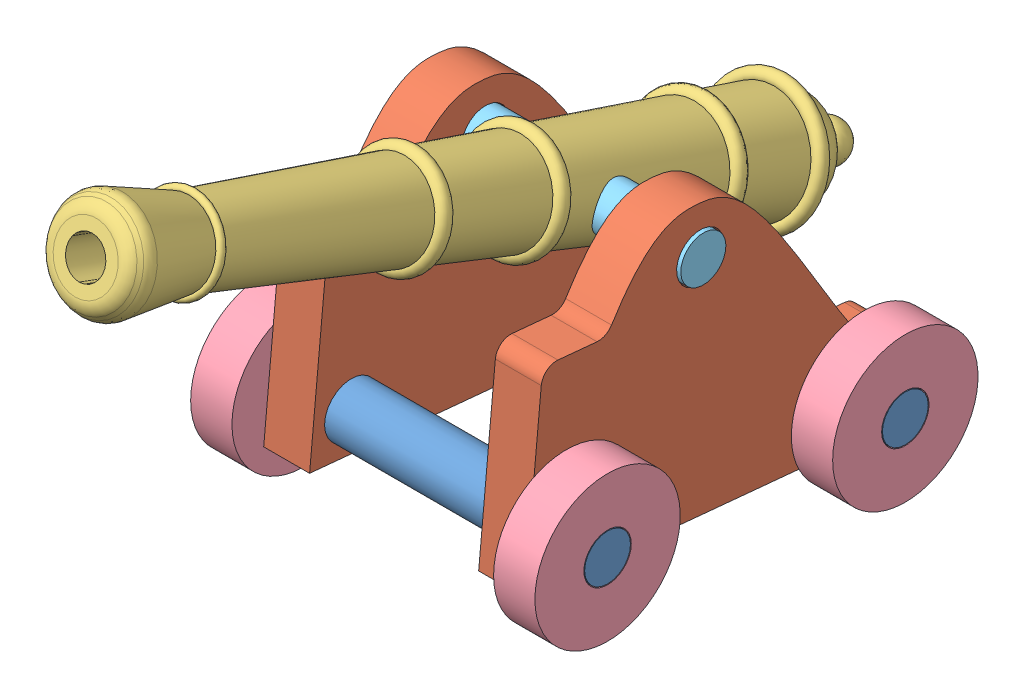
SolidWorks assembly ToyCannon, configuration Default. Lengths in mm.
Overall size (57.15 89.23 132.99).
10 component instances, 5 part files, 21 mates.
Components (placement in the parent):
- Axle-1: Axle [Default] at (20.2048 30.8146 43.7896) size (57.15 8.89 8.89)
- SideSupports-1: SideSupports [Default] at (2.4248 44.3939 17.6176) x (0 0.094911 0.995486) z (-1 0 0) size (62.23 44.95 7.62)
- Axle-2: Axle [Default] at (20.2048 26.1016 -5.6432) size (57.15 8.89 8.89)
- SideSupports-2: SideSupports [Default] at (38.1118 44.3939 17.6176) x (0 0.094911 0.995486) z (-1 0 0) size (62.23 44.95 7.62)
- Barrel-1: Barrel [Default] at (20.2048 65.3462 37.7707) x (1 0 0) z (0 -0.939693 0.34202) size (20.53 134.05 20.53)
- Wheel-1: Wheel [Default] at (-4.8142 26.1016 -5.6432) x (1 0 0) z (0 0.759231 0.650821) size (6.86 24.13 24.13)
- Wheel-2: Wheel [Default] at (-4.9412 30.8146 43.7896) size (6.86 24.13 24.13)
- Wheel-3: Wheel [Default] at (45.3508 26.1016 -5.6432) size (6.86 24.13 24.13)
- Wheel-4: Wheel [Default] at (45.3508 30.8146 43.7896) size (6.86 24.13 24.13)
- BarrelAxle-1: BarrelAxle [Default] at (20.2048 59.4392 21.5414) x (1 0 0) z (0 0.428897 0.903354) size (44.45 7.62 7.62)
Mates (geometry in assembly coordinates):
- Concentric1: concentric anti-aligned: cylinder of Axle-2 through (48.7798 26.1016 -5.6432) axis (-1 0 0) radius 4.445; cylinder of SideSupports-2 through (34.3018 26.1016 -5.6432) axis (1 0 0) radius 3.937
- Concentric2: concentric anti-aligned: cylinder of SideSupports-1 through (-1.3852 26.1016 -5.6432) axis (1 0 0) radius 3.937; cylinder of Axle-2 through (48.7798 26.1016 -5.6432) axis (-1 0 0) radius 4.445
- Concentric3: concentric anti-aligned: cylinder of Axle-1 through (48.7798 30.8146 43.7896) axis (-1 0 0) radius 4.445; cylinder of SideSupports-2 through (34.3018 30.8146 43.7896) axis (1 0 0) radius 3.937
- Concentric4: concentric anti-aligned: cylinder of Axle-1 through (48.7798 30.8146 43.7896) axis (-1 0 0) radius 4.445; cylinder of SideSupports-1 through (-1.3852 30.8146 43.7896) axis (1 0 0) radius 3.937
- Angle1: planar angle = 2.792527 rad aligned: plane of Barrel-1 through (20.2048 65.3462 37.7707) normal (0 -0.939693 0.34202); plane of assembly through (0 0 0) normal (0 1 0)
- Coincident3: coincident aligned: plane of Axle-2 through (20.2048 26.1016 -5.6432) normal (1 0 0); plane of Barrel-1
- Coincident4: coincident aligned: plane of Axle-1 through (20.2048 30.8146 43.7896) normal (1 0 0); plane of Barrel-1
- Concentric8: concentric anti-aligned: cylinder of Axle-1 through (48.7798 30.8146 43.7896) axis (-1 0 0) radius 4.445; cylinder of Wheel-4 through (41.9218 30.8146 43.7896) axis (1 0 0) radius 3.937
- Concentric9: concentric anti-aligned: cylinder of Axle-1 through (48.7798 30.8146 43.7896) axis (-1 0 0) radius 4.445; cylinder of Wheel-2 through (-8.3702 30.8146 43.7896) axis (1 0 0) radius 3.937
- Concentric10: concentric anti-aligned: cylinder of Axle-2 through (48.7798 26.1016 -5.6432) axis (-1 0 0) radius 4.445; cylinder of Wheel-1 through (-8.2432 26.1016 -5.6432) axis (1 0 0) radius 3.937
- Coincident6: coincident aligned: plane of Axle-1 through (-8.3702 30.8146 43.7896) normal (-1 0 0); plane of Wheel-2 through (-8.3702 30.8146 43.7896) normal (-1 0 0)
- Coincident7: coincident aligned: plane of Axle-1 through (48.7798 30.8146 43.7896) normal (1 0 0); plane of Wheel-4 through (48.7798 30.8146 43.7896) normal (1 0 0)
- Coincident8: coincident aligned: plane of Axle-2 through (48.7798 26.1016 -5.6432) normal (1 0 0); plane of Wheel-3 through (48.7798 26.1016 -5.6432) normal (1 0 0)
- Concentric12: concentric anti-aligned: cylinder of Axle-2 through (48.7798 26.1016 -5.6432) axis (-1 0 0) radius 4.445; cylinder of Wheel-3 through (41.9218 26.1016 -5.6432) axis (1 0 0) radius 3.937
- Coincident11: coincident anti-aligned: plane of SideSupports-1 through (-1.3852 30.8091 -9.7917) normal (-1 0 0); plane of Wheel-1 through (-1.3852 26.1016 -5.6432) normal (1 0 0)
- Coincident10: coincident anti-aligned: plane of SideSupports-2 through (41.9218 30.8091 -9.7917) normal (1 0 0); plane of Wheel-3 through (41.9218 26.1016 -5.6432) normal (-1 0 0)
- Concentric13: concentric anti-aligned: cylinder of Barrel-1 through (10.6798 59.4392 21.5414) axis (1 0 0) radius 3.81; cylinder of BarrelAxle-1 through (42.4298 59.4392 21.5414) axis (-1 0 0) radius 3.81
- Concentric14: concentric anti-aligned: cylinder of SideSupports-2 through (34.3018 59.4392 21.5414) axis (1 0 0) radius 3.937; cylinder of BarrelAxle-1 through (42.4298 59.4392 21.5414) axis (-1 0 0) radius 3.81
- Concentric15: concentric anti-aligned: cylinder of SideSupports-1 through (-1.3852 59.4392 21.5414) axis (1 0 0) radius 3.937; cylinder of BarrelAxle-1 through (42.4298 59.4392 21.5414) axis (-1 0 0) radius 3.81
- Coincident12: coincident aligned: plane of Barrel-1; plane of BarrelAxle-1
- Coincident13: coincident anti-aligned: plane of SideSupports-1 through (6.2348 30.8091 -9.7917) normal (1 0 0); plane of Axle-2 through (6.2348 26.1016 -5.6432) normal (-1 0 0)
